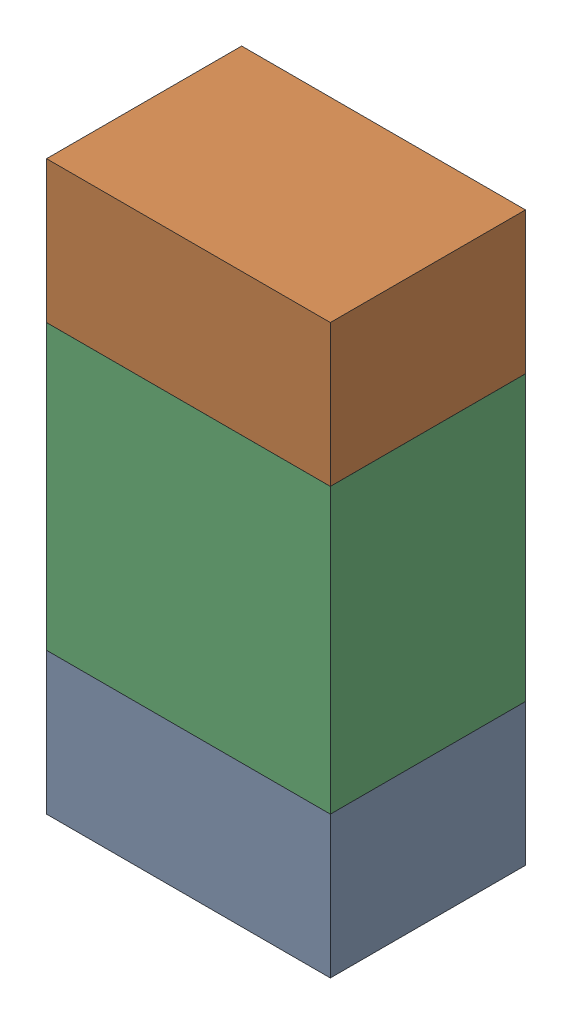
SolidWorks assembly R28, configuration ﾃﾞﾌｫﾙﾄ. Lengths in mm.
Overall size (0.8 1.6 0.55).
6 component instances, 2 part files, 0 mates.
Components (placement in the parent):
- 689261784-1: 689261784 [ﾃﾞﾌｫﾙﾄ] at (24.4999 69.1501 0) size (0.8 0.4 0.55)
  - Extruded_34-1: Extruded_34 [ﾃﾞﾌｫﾙﾄ] at origin size (0.8 0.4 0.55)
- 689261784-2: 689261784 [ﾃﾞﾌｫﾙﾄ] at (24.4999 70.3501 0) size (0.8 0.4 0.55)
  - Extruded_34-1: Extruded_34 [ﾃﾞﾌｫﾙﾄ] at origin size (0.8 0.4 0.55)
- 689261648-1: 689261648 [ﾃﾞﾌｫﾙﾄ] at (24.4999 69.75 0) size (0.8 0.8 0.55)
  - Extruded_33-1: Extruded_33 [ﾃﾞﾌｫﾙﾄ] at origin size (0.8 0.8 0.55)
